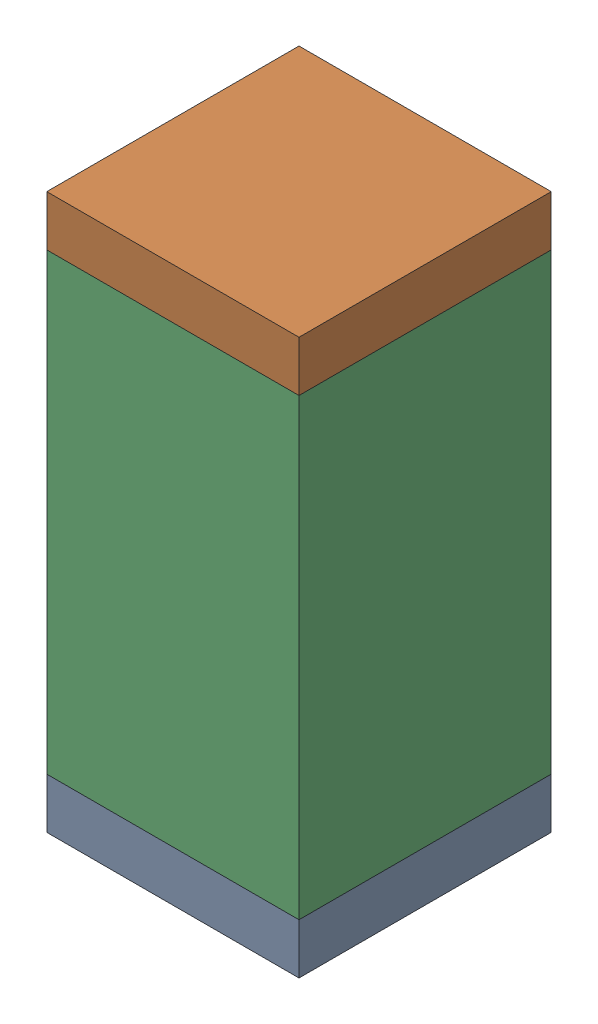
SolidWorks assembly C15, configuration Default. Lengths in mm.
Overall size (0.5 1.1 0.5).
6 component instances, 2 part files, 0 mates.
Components (placement in the parent):
- 810157360-1: 810157360 [Default] at (134.5 13.25 0) size (0.5 0.1 0.5)
  - Extruded_9-1: Extruded_9 [Default] at origin size (0.5 0.1 0.5)
- 810157360-2: 810157360 [Default] at (134.5 14.25 0) size (0.5 0.1 0.5)
  - Extruded_9-1: Extruded_9 [Default] at origin size (0.5 0.1 0.5)
- 791586336-1: 791586336 [Default] at (134.5 13.75 0) size (0.5 0.9 0.5)
  - Extruded_8-1: Extruded_8 [Default] at origin size (0.5 0.9 0.5)
